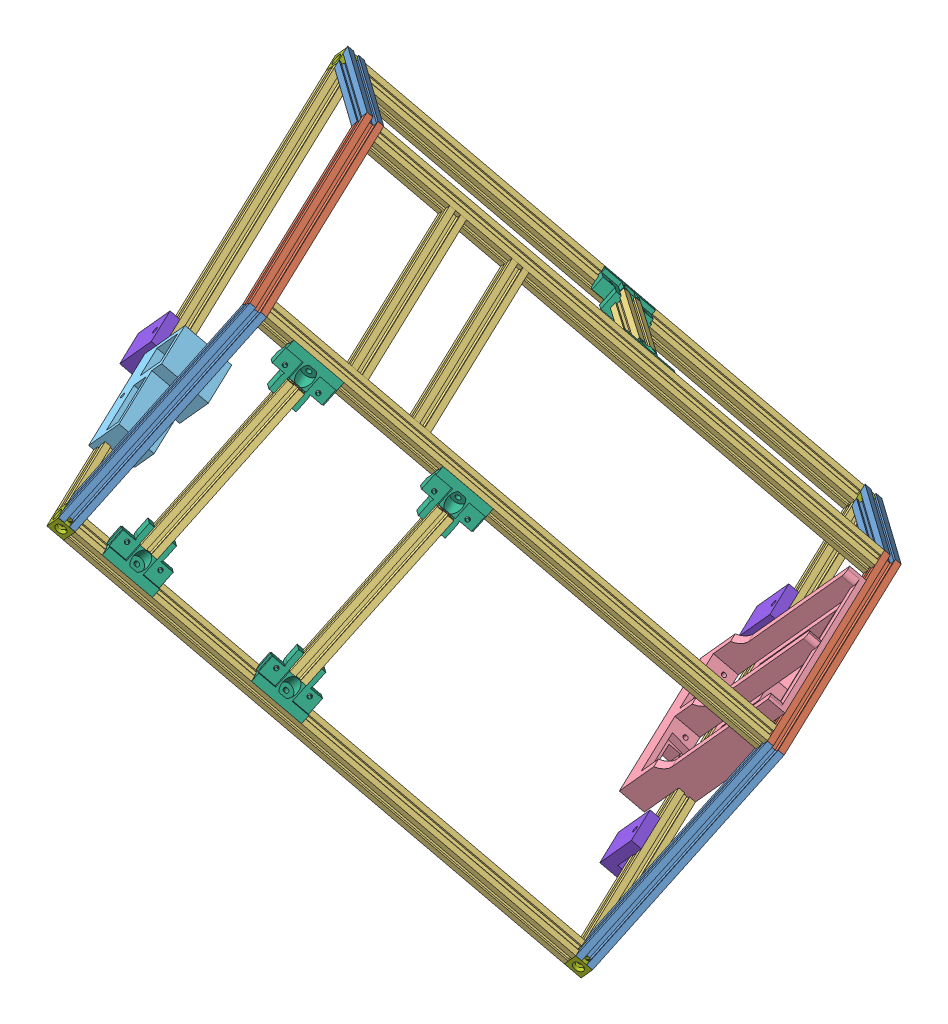
SolidWorks assembly ElectronicalBlock, configuration Default. Lengths in mm.
Overall size (353.4 324.72 408.45).
44 component instances, 11 part files, 96 mates.
Components (placement in the parent):
- MakerbeamVShapeElectronicalBlock-1: MakerbeamVShapeElectronicalBlock [Default] at (224.5108 -4.278 -44.3554) x (-0.701121 -0.374908 -0.606525) z (0.238672 0.678157 -0.695081) size (10 10 130)
- MakerbeamVShapeCentralElectronicalBlock-1: MakerbeamVShapeCentralElectronicalBlock [Default] at (214.846 108.8376 -246.4171) x (-0.664534 -0.74463 0.062619) z (0.327001 -0.21443 0.920375) size (10 10 125)
- MakerbeamVShapeElectronicalBlock-2: MakerbeamVShapeElectronicalBlock [Default] at (125.8295 60.432 -322.1031) x (-0.238672 -0.678157 0.695081) z (0.701121 0.374908 0.606525) size (10 10 130)
- Makerbeam50-1000mm-1: Makerbeam50-1000mm [288mm] at (127.2474 57.7735 -315.2814) x (0.664534 0.74463 -0.062619) z (0.327001 -0.21443 0.920375) size (10 10 288)
- Makerbeam50-1000mm-2: Makerbeam50-1000mm [300mm] at (-79.3205 251.6353 -202.1561) x (0.664534 0.74463 -0.062619) z (0.671911 -0.632097 -0.385991) size (10 10 300)
- Makerbeam50-1000mm-3: Makerbeam50-1000mm [300mm] at (11.5481 300.5551 -124.088) x (0.664534 0.74463 -0.062619) z (0.671911 -0.632097 -0.385991) size (10 10 300)
- Makerbeam50-1000mm-4: Makerbeam50-1000mm [300mm] at (49.0974 275.9323 -18.4022) x (0.664534 0.74463 -0.062619) z (0.671911 -0.632097 -0.385991) size (10 10 300)
- Makerbeam50-1000mm-5: Makerbeam50-1000mm [300mm] at (18.1259 187.7352 72.1157) x (0.664534 0.74463 -0.062619) z (0.671911 -0.632097 -0.385991) size (10 10 300)
- MakerbeamVShapeCentralElectronicalBlock-2: MakerbeamVShapeCentralElectronicalBlock [Default] at (6.4977 304.8243 -126.9172) x (-0.664534 -0.74463 0.062619) z (0.327001 -0.21443 0.920375) size (10 10 125)
- MakerbeamVShapeElectronicalBlock-3: MakerbeamVShapeElectronicalBlock [Default] at (16.1625 191.7087 75.1445) x (-0.701121 -0.374908 -0.606525) z (0.238672 0.678157 -0.695081) size (10 10 130)
- MakerbeamVShapeElectronicalBlock-4: MakerbeamVShapeElectronicalBlock [Default] at (-82.5188 256.4187 -202.6032) x (-0.238672 -0.678157 0.695081) z (0.701121 0.374908 0.606525) size (10 10 130)
- BatteriesBottomRack-1: BatteriesBottomRack [Default] at (181.2062 27.3347 -184.4602) x (-0.327001 0.21443 -0.920375) z (0.664534 0.74463 -0.062619) size (87 25 122.5)
- Makerbeam50-1000mm-6: Makerbeam50-1000mm [288mm] at (-81.045 253.7236 -195.6242) x (0.671911 -0.632097 -0.385991) z (0.327001 -0.21443 0.920375) size (10 10 288)
- PowerSwitchSupport-1: PowerSwitchSupport [Default] at (-6.8274 221.3425 7.3227) x (0.327001 -0.21443 0.920375) z (0.671911 -0.632097 -0.385991) size (60 35 28)
- WindowFixationMiddlesWithMakerBeam-1: WindowFixationMiddlesWithMakerBeam [Default] at (58.4475 311.7823 0.7661) x (-0.701343 -0.375537 -0.60588) z (-0.238021 -0.677809 0.695644) size (35.21 42 131.54)
  - Makerbeam50-1000mm-1: Makerbeam50-1000mm [100mm] at (29.5633 55.1843 28.8182) size (10 10 100)
  - WindowFixationMiddle-1: WindowFixationMiddle [Default] at (24.5633 55.0843 143.3182) x (-0.707107 0 -0.707107) z (0 -1 0) size (19.74 30.05 41)
  - WindowFixationMiddle-2: WindowFixationMiddle [Default] at (24.5633 55.0843 13.1973) x (-0.707107 0 0.707107) z (0 1 0) size (19.74 30.05 41)
- MakerBeam-cube-1: MakerBeam-cube [Default] at (221.4238 -3.9823 -50.2134) x (0.664534 0.74463 -0.062619) z (0.327001 -0.21443 0.920375) size (10 10 10)
- MakerBeam-cube-2: MakerBeam-cube [Default] at (127.2474 57.7735 -315.2814) x (0.664534 0.74463 -0.062619) z (-0.327001 0.21443 -0.920375) size (10 10 10)
- WindowFixationMiddlesWithMakerBeam-2: WindowFixationMiddlesWithMakerBeam [Default] at (-11.4548 201.6866 -272.8859) x (-0.23502 -0.676197 0.698229) z (0.702354 0.378432 0.602899) size (35.21 42 131.54)
  - Makerbeam50-1000mm-1: Makerbeam50-1000mm [100mm] at (29.5633 55.1843 28.8182) size (10 10 100)
  - WindowFixationMiddle-1: WindowFixationMiddle [Default] at (24.5633 55.0843 143.3182) x (-0.707107 0 -0.707107) z (0 -1 0) size (19.74 30.05 41)
  - WindowFixationMiddle-2: WindowFixationMiddle [Default] at (24.5633 55.0843 13.1973) x (-0.707107 0 0.707107) z (0 1 0) size (19.74 30.05 41)
- MakerBeam-cube-3: MakerBeam-cube [Default] at (-81.045 253.7236 -195.6242) x (-0.664534 -0.74463 0.062619) z (-0.327001 0.21443 -0.920375) size (10 10 10)
- ElectronicalToMechanicalTopFixation-1: ElectronicalToMechanicalTopFixation [Default] at (-32.013 212.2001 -29.3196) x (-0.327001 0.21443 -0.920375) z (-0.671911 0.632097 0.385991) size (20 27.5 16)
- Bracket_135Deg_25mm-1: Bracket_135Deg_25mm [Default] at (1.1699 303.3735 -120.8618) x (0.701121 0.374908 0.606525) z (0.671911 -0.632097 -0.385991) (suppressed, hidden)
- Bracket_135Deg_25mm-2: Bracket_135Deg_25mm [Default] at (39.3361 278.3461 -13.4396) x (0.327001 -0.21443 0.920375) z (0.671911 -0.632097 -0.385991) (suppressed, hidden)
- BracketPlainCorner45Deg_40mm-1: BracketPlainCorner45Deg_40mm [Default] at (-55.5212 273.0592 -169.9042) x (-0.701121 -0.374908 -0.606525) z (0.671911 -0.632097 -0.385991) (suppressed, hidden)
- Bracket_135Deg_25mm-3: Bracket_135Deg_25mm [Default] at (247.6844 82.3594 -132.9395) x (0.327001 -0.21443 0.920375) z (0.671911 -0.632097 -0.385991) (suppressed, hidden)
- Bracket_135Deg_25mm-4: Bracket_135Deg_25mm [Default] at (209.5182 107.3868 -240.3617) x (0.702572 0.37906 0.602251) z (0.671911 -0.632097 -0.385991) (suppressed, hidden)
- BracketPlainCorner45Deg_40mm-2: BracketPlainCorner45Deg_40mm [Default] at (0.239 207.2813 34.8779) x (0.327001 -0.21443 0.920375) z (0.671911 -0.632097 -0.385991) (suppressed, hidden)
- MakerBeam-cube-4: MakerBeam-cube [Default] at (13.1313 191.9678 69.4438) x (0.664534 0.74463 -0.062619) z (0.327001 -0.21443 0.920375) size (10 10 10)
- BracketPlainCorner45Deg_40mm-3: BracketPlainCorner45Deg_40mm [Default] at (146.452 50.1247 -282.2792) x (-0.327001 0.21443 -0.920375) z (-0.671911 0.632097 0.385991) (suppressed, hidden)
- BracketPlainCorner45Deg_40mm-4: BracketPlainCorner45Deg_40mm [Default] at (235.105 21.2041 -80.5966) x (-0.238672 -0.678157 0.695081) z (-0.671911 0.632097 0.385991) (suppressed, hidden)
- Pièce2^ElectronicalBlock-1: Pièce2^ElectronicalBlock [Default] at origin (virtual)
- ElectronicalToMechanicalTopFixation-2: ElectronicalToMechanicalTopFixation [Default] at (140.9633 39.4084 -248.3773) x (-0.327001 0.21443 -0.920375) z (-0.671911 0.632097 0.385991) size (20 27.5 16)
- ElectronicalToMechanicalTopFixation-3: ElectronicalToMechanicalTopFixation [Default] at (189.3595 7.6728 -112.1618) x (-0.327001 0.21443 -0.920375) z (-0.671911 0.632097 0.385991) size (20 27.5 16)
- Makerbeam50-1000mm-8: Makerbeam50-1000mm [105mm] at (46.9272 267.7383 -138.871) x (0.671911 -0.632097 -0.385991) z (0.327001 -0.21443 0.920375) size (10 10 105)
- Makerbeam50-1000mm-9: Makerbeam50-1000mm [105mm] at (71.9912 244.1436 -153.4588) x (0.664534 0.74463 -0.062619) z (0.327001 -0.21443 0.920375) size (10 10 105)
- WindowFixationMiddlesWithMakerBeam-3: WindowFixationMiddlesWithMakerBeam [Default] at (118.6058 255.3059 -33.6458) x (-0.701121 -0.374908 -0.606525) z (-0.238672 -0.678157 0.695081) size (35.21 42 131.54)
  - Makerbeam50-1000mm-1: Makerbeam50-1000mm [100mm] at (29.5633 55.1843 28.8182) size (10 10 100)
  - WindowFixationMiddle-1: WindowFixationMiddle [Default] at (24.5633 55.0843 143.3182) x (-0.707107 0 -0.707107) z (0 -1 0) size (19.74 30.05 41)
  - WindowFixationMiddle-2: WindowFixationMiddle [Default] at (24.5633 55.0843 13.1973) x (-0.707107 0 0.707107) z (0 1 0) size (19.74 30.05 41)
Mates (geometry in assembly coordinates):
- Coïncidente3: coincident aligned: plane of MakerbeamVShapeElectronicalBlock-1 through (255.6842 88.9175 -129.7534) normal (-0.671911 0.632097 0.385991); plane of MakerbeamVShapeCentralElectronicalBlock-1 through (253.3584 86.3113 -129.5342) normal (-0.671911 0.632097 0.385991)
- Coïncidente4: coincident anti-aligned: plane of MakerbeamVShapeElectronicalBlock-1 through (254.4035 76.0384 -136.7994) normal (-0.047803 0.483065 -0.874279); plane of MakerbeamVShapeCentralElectronicalBlock-1 through (247.6844 82.3594 -132.9395) normal (0.047803 -0.483065 0.874279)
- Coïncidente5: coincident anti-aligned: line of MakerbeamVShapeElectronicalBlock-1 through (255.6842 88.9175 -129.7534) axis (0.671911 -0.632097 -0.385991); line of MakerbeamVShapeCentralElectronicalBlock-1 through (258.0359 86.7052 -131.1043) axis (-0.671911 0.632097 0.385991)
- Coïncidente8: coincident aligned: line of MakerbeamVShapeCentralElectronicalBlock-1 through (217.1608 113.5089 -246.1512) axis (-0.671911 0.632097 0.385991); line of MakerbeamVShapeElectronicalBlock-2 through (217.1608 113.5089 -246.1512) axis (-0.671911 0.632097 0.385991)
- Coïncidente9: coincident aligned: plane of MakerbeamVShapeElectronicalBlock-1 through (251.127 86.4806 -133.6958) normal (-0.671911 0.632097 0.385991); plane of Makerbeam50-1000mm-1 through (219.061 0.2951 -48.3774) normal (-0.671911 0.632097 0.385991)
- Coïncidente10: coincident anti-aligned: plane of MakerbeamVShapeElectronicalBlock-1 through (226.7515 -2.5314 -56.2687) normal (-0.664534 -0.74463 0.062619); plane of Makerbeam50-1000mm-1 through (221.3869 2.9013 -48.5965) normal (0.664534 0.74463 -0.062619)
- Coïncidente11: coincident anti-aligned: plane of Makerbeam50-1000mm-1 through (214.7415 -4.545 -47.9703) normal (-0.671911 0.632097 0.385991); plane of Makerbeam50-1000mm-2 through (122.2529 62.0062 -317.9533) normal (0.671911 -0.632097 -0.385991)
- Coïncidente12: coincident aligned: plane of Makerbeam50-1000mm-1 through (221.3869 2.9013 -48.5965) normal (0.664534 0.74463 -0.062619); plane of Makerbeam50-1000mm-2 through (125.085 66.051 -319.6469) normal (0.664534 0.74463 -0.062619)
- Coïncidente13: coincident anti-aligned: plane of MakerbeamVShapeCentralElectronicalBlock-1 through (253.3584 86.3113 -129.5342) normal (-0.671911 0.632097 0.385991); plane of Makerbeam50-1000mm-3 through (213.1214 110.926 -239.8853) normal (0.671911 -0.632097 -0.385991)
- Coïncidente14: coincident aligned: plane of MakerbeamVShapeCentralElectronicalBlock-1 through (255.6842 88.9175 -129.7534) normal (0.664534 0.74463 -0.062619); plane of Makerbeam50-1000mm-3 through (218.0791 113.577 -235.5965) normal (0.664534 0.74463 -0.062619)
- Coïncidente15: coincident aligned: plane of MakerbeamVShapeCentralElectronicalBlock-1 through (253.3584 86.3113 -129.5342) normal (-0.671911 0.632097 0.385991); plane of MakerbeamVShapeElectronicalBlock-2 through (213.9737 113.3477 -242.3674) normal (-0.671911 0.632097 0.385991)
- Coïncidente16: coincident anti-aligned: plane of MakerbeamVShapeCentralElectronicalBlock-1 through (253.3584 86.3113 -129.5342) normal (-0.671911 0.632097 0.385991); plane of Makerbeam50-1000mm-4 through (250.6707 86.3032 -134.1994) normal (0.671911 -0.632097 -0.385991)
- Coïncidente17: coincident aligned: plane of MakerbeamVShapeCentralElectronicalBlock-1 through (255.6842 88.9175 -129.7534) normal (0.664534 0.74463 -0.062619); plane of Makerbeam50-1000mm-4 through (255.6284 88.9542 -129.9106) normal (0.664534 0.74463 -0.062619)
- Coïncidente18: coincident anti-aligned: plane of Makerbeam50-1000mm-1 through (214.7415 -4.545 -47.9703) normal (-0.671911 0.632097 0.385991); plane of Makerbeam50-1000mm-5 through (219.6992 -1.894 -43.6816) normal (0.671911 -0.632097 -0.385991)
- Coïncidente19: coincident aligned: plane of Makerbeam50-1000mm-1 through (221.3869 2.9013 -48.5965) normal (0.664534 0.74463 -0.062619); plane of Makerbeam50-1000mm-5 through (224.6569 0.757 -39.3928) normal (0.664534 0.74463 -0.062619)
- Coïncidente20: coincident anti-aligned: plane of Makerbeam50-1000mm-3 through (11.5481 300.5551 -124.088) normal (-0.671911 0.632097 0.385991); plane of MakerbeamVShapeCentralElectronicalBlock-2 through (54.055 278.5833 -14.1134) normal (0.671911 -0.632097 -0.385991)
- Coïncidente21: coincident aligned: plane of Makerbeam50-1000mm-3 through (218.0791 113.577 -235.5965) normal (0.664534 0.74463 -0.062619); plane of MakerbeamVShapeCentralElectronicalBlock-2 through (51.7034 280.7956 -12.7624) normal (0.664534 0.74463 -0.062619)
- Coïncidente22: coincident anti-aligned: plane of MakerbeamVShapeCentralElectronicalBlock-2 through (39.3361 278.3461 -13.4396) normal (0.047803 -0.483065 0.874279); plane of MakerbeamVShapeElectronicalBlock-3 through (46.0552 272.0252 -17.2995) normal (-0.047803 0.483065 -0.874279)
- Coïncidente23: coincident aligned: plane of MakerbeamVShapeCentralElectronicalBlock-2 through (45.0101 282.298 -10.0343) normal (-0.671911 0.632097 0.385991); plane of MakerbeamVShapeElectronicalBlock-3 through (47.3359 284.9042 -10.2535) normal (-0.671911 0.632097 0.385991)
- Coïncidente24: coincident anti-aligned: line of MakerbeamVShapeCentralElectronicalBlock-2 through (49.6876 282.6919 -11.6044) axis (-0.671911 0.632097 0.385991); line of MakerbeamVShapeElectronicalBlock-3 through (47.3359 284.9042 -10.2535) axis (0.671911 -0.632097 -0.385991)
- Coïncidente25: coincident anti-aligned: plane of MakerbeamVShapeCentralElectronicalBlock-1 through (209.5182 107.3868 -240.3617) normal (-0.556416 -0.08685 -0.826352); plane of MakerbeamVShapeElectronicalBlock-2 through (209.5182 107.3868 -240.3617) normal (0.556416 0.08685 0.826352)
- Coïncidente26: coincident aligned: plane of MakerbeamVShapeCentralElectronicalBlock-2 through (45.0101 282.298 -10.0343) normal (-0.671911 0.632097 0.385991); plane of MakerbeamVShapeElectronicalBlock-4 through (5.6254 309.3344 -122.8676) normal (-0.671911 0.632097 0.385991)
- Coïncidente27: coincident anti-aligned: plane of MakerbeamVShapeCentralElectronicalBlock-2 through (1.1699 303.3735 -120.8618) normal (-0.556416 -0.08685 -0.826352); plane of MakerbeamVShapeElectronicalBlock-4 through (1.1699 303.3735 -120.8618) normal (0.556416 0.08685 0.826352)
- Coïncidente28: coincident aligned: line of MakerbeamVShapeCentralElectronicalBlock-2 through (8.8125 309.4956 -126.6513) axis (-0.671911 0.632097 0.385991); line of MakerbeamVShapeElectronicalBlock-4 through (8.8125 309.4956 -126.6513) axis (-0.671911 0.632097 0.385991)
- Coïncidente29: coincident aligned: plane of Makerbeam50-1000mm-1 through (225.7801 -6.0258 -52.2373) normal (0.671911 -0.632097 -0.385991); plane of BatteriesBottomRack-1 through (228.4511 105.5407 -230.2887) normal (0.671911 -0.632097 -0.385991)
- Coïncidente31: coincident anti-aligned: plane of Makerbeam50-1000mm-1 through (221.3869 2.9013 -48.5965) normal (0.664534 0.74463 -0.062619); plane of BatteriesBottomRack-1 through (181.2062 27.3347 -184.4602) normal (-0.664534 -0.74463 0.062619)
- Coïncidente32: coincident anti-aligned: plane of MakerbeamVShapeElectronicalBlock-4 through (-80.0605 259.9375 -191.1326) normal (-0.664534 -0.74463 0.062619); plane of Makerbeam50-1000mm-6 through (17.4619 194.7428 68.5517) normal (0.664534 0.74463 -0.062619)
- Coïncidente34: coincident aligned: plane of MakerbeamVShapeElectronicalBlock-4 through (5.6254 309.3344 -122.8676) normal (-0.671911 0.632097 0.385991); plane of Makerbeam50-1000mm-6 through (10.7686 196.2452 71.2798) normal (-0.671911 0.632097 0.385991)
- Coïncidente36: coincident anti-aligned: plane of Makerbeam50-1000mm-6 through (13.0944 198.8514 71.0606) normal (0.664534 0.74463 -0.062619); plane of PowerSwitchSupport-1 through (-6.1675 207.6525 -28.6967) normal (-0.664534 -0.74463 0.062619)
- Parallèle1: parallel aligned: plane of Makerbeam50-1000mm-6 through (6.4491 191.4051 71.6868) normal (-0.671911 0.632097 0.385991); plane of PowerSwitchSupport-1 through (-6.8274 221.3425 7.3227) normal (-0.671911 0.632097 0.385991)
- Coïncidente38: coincident anti-aligned: plane of Makerbeam50-1000mm-6 through (10.7686 196.2452 71.2798) normal (-0.671911 0.632097 0.385991); plane of PowerSwitchSupport-1 through (-4.8116 219.4462 6.1647) normal (0.671911 -0.632097 -0.385991)
- Coïncidente39: coincident aligned: line of Makerbeam50-1000mm-4 through (255.6284 88.9542 -129.9106) axis (-0.671911 0.632097 0.385991); line of WindowFixationMiddlesWithMakerBeam-1/WindowFixationMiddle-2 through (85.1694 249.3125 -31.9876) axis (-0.671911 0.632097 0.385991)
- Coïncidente40: coincident anti-aligned: line of Makerbeam50-1000mm-5 through (224.6569 0.757 -39.3928) axis (-0.671911 0.632097 0.385991); line of WindowFixationMiddlesWithMakerBeam-1/WindowFixationMiddle-1 through (34.0406 180.0784 70.11) axis (0.671911 -0.632097 -0.385991)
- Coïncidente41: coincident anti-aligned: plane of Makerbeam50-1000mm-1 through (221.4238 -3.9823 -50.2134) normal (0.327001 -0.21443 0.920375); plane of MakerBeam-cube-1 through (221.4238 -3.9823 -50.2134) normal (-0.327001 0.21443 -0.920375)
- Coïncidente42: coincident aligned: plane of Makerbeam50-1000mm-1 through (217.0932 -6.7573 -49.3213) normal (-0.664534 -0.74463 0.062619); plane of MakerBeam-cube-1 through (224.7307 -13.0102 -42.6265) normal (-0.664534 -0.74463 0.062619)
- Coïncidente43: coincident aligned: plane of Makerbeam50-1000mm-5 through (222.331 -1.8492 -39.1736) normal (0.327001 -0.21443 0.920375); plane of MakerBeam-cube-1 through (224.6938 -6.1266 -41.0096) normal (0.327001 -0.21443 0.920375)
- Coïncidente44: coincident aligned: plane of Makerbeam50-1000mm-1 through (223.7865 -8.2597 -52.0494) normal (0.671911 -0.632097 -0.385991); plane of MakerBeam-cube-1 through (231.376 -5.5639 -43.2527) normal (0.671911 -0.632097 -0.385991)
- Coïncidente45: coincident anti-aligned: line of MakerbeamVShapeElectronicalBlock-1 through (224.6569 0.757 -39.3928) axis (0.671911 -0.632097 -0.385991); line of Makerbeam50-1000mm-5 through (224.6569 0.757 -39.3928) axis (-0.671911 0.632097 0.385991)
- Coïncidente46: coincident anti-aligned: plane of Makerbeam50-1000mm-1 through (127.2474 57.7735 -315.2814) normal (-0.327001 0.21443 -0.920375); plane of MakerBeam-cube-2 through (127.2474 57.7735 -315.2814) normal (0.327001 -0.21443 0.920375)
- Coïncidente47: coincident aligned: plane of Makerbeam50-1000mm-1 through (221.4606 -10.8659 -51.8302) normal (-0.664534 -0.74463 0.062619); plane of MakerBeam-cube-2 through (117.2952 59.3552 -322.2421) normal (-0.664534 -0.74463 0.062619)
- Coïncidente48: coincident aligned: plane of Makerbeam50-1000mm-1 through (214.7415 -4.545 -47.9703) normal (-0.671911 0.632097 0.385991); plane of MakerBeam-cube-2 through (123.9405 66.8015 -322.8683) normal (-0.671911 0.632097 0.385991)
- Coïncidente49: coincident anti-aligned: line of Makerbeam50-1000mm-3 through (214.8091 115.7213 -244.8002) axis (-0.671911 0.632097 0.385991); line of WindowFixationMiddlesWithMakerBeam-2/WindowFixationMiddle-1 through (110.3656 213.976 -184.8009) axis (0.671911 -0.632097 -0.385991)
- Coïncidente51: coincident anti-aligned: line of Makerbeam50-1000mm-2 through (123.9405 66.8015 -322.8683) axis (-0.671911 0.632097 0.385991); line of MakerBeam-cube-2 through (123.9405 66.8015 -322.8683) axis (0.671911 -0.632097 -0.385991)
- Coaxiale1: concentric aligned: cylinder of Makerbeam50-1000mm-2 through (122.2529 62.0062 -317.9533) axis (-0.671911 0.632097 0.385991) radius 1.25; cylinder of MakerBeam-cube-3 through (-80.6643 252.8995 -201.3841) axis (-0.671911 0.632097 0.385991) radius 3
- Coïncidente52: coincident aligned: plane of Makerbeam50-1000mm-2 through (119.6211 61.9614 -322.4612) normal (-0.327001 0.21443 -0.920375); plane of MakerBeam-cube-3 through (-84.315 255.8679 -204.828) normal (-0.327001 0.21443 -0.920375)
- Coïncidente53: coincident aligned: plane of Makerbeam50-1000mm-6 through (10.7686 196.2452 71.2798) normal (-0.671911 0.632097 0.385991); plane of MakerBeam-cube-3 through (-90.9972 255.3052 -202.5849) normal (-0.671911 0.632097 0.385991)
- Coïncidente54: coincident anti-aligned: plane of Makerbeam50-1000mm-6 through (-81.045 253.7236 -195.6242) normal (-0.327001 0.21443 -0.920375); plane of MakerBeam-cube-3 through (-81.045 253.7236 -195.6242) normal (0.327001 -0.21443 0.920375)
- Coïncidente56: coincident anti-aligned: plane of Makerbeam50-1000mm-6 through (10.7686 196.2452 71.2798) normal (-0.671911 0.632097 0.385991); plane of ElectronicalToMechanicalTopFixation-1 through (-32.013 212.2001 -29.3196) normal (0.671911 -0.632097 -0.385991)
- Coïncidente57: coincident anti-aligned: plane of Makerbeam50-1000mm-6 through (6.4491 191.4051 71.6868) normal (-0.671911 0.632097 0.385991); plane of ElectronicalToMechanicalTopFixation-1 through (-32.013 212.2001 -29.3196) normal (0.671911 -0.632097 -0.385991)
- Coïncidente58: coincident aligned: plane of Makerbeam50-1000mm-6 through (13.0944 198.8514 71.0606) normal (0.664534 0.74463 -0.062619); plane of ElectronicalToMechanicalTopFixation-1 through (-23.6371 224.087 -18.6609) normal (0.664534 0.74463 -0.062619)
- Coïncidente59: coincident aligned: plane of MakerbeamVShapeElectronicalBlock-4 through (4.9094 307.2999 -120.7823) normal (-0.671911 0.632097 0.385991); plane of Bracket_135Deg_25mm-1 through (-6.7664 290.8717 -114.2041) normal (-0.671911 0.632097 0.385991)
- Coïncidente60: coincident anti-aligned: plane of MakerbeamVShapeElectronicalBlock-4 through (6.4258 302.7141 -119.7005) normal (-0.238672 -0.678157 0.695081); plane of Bracket_135Deg_25mm-1 through (-9.639 287.6798 -139.8849) normal (0.238672 0.678157 -0.695081)
- Coïncidente61: coincident: point of MakerbeamVShapeCentralElectronicalBlock-2; point of Bracket_135Deg_25mm-1
- Coïncidente62: coincident anti-aligned: plane of MakerbeamVShapeCentralElectronicalBlock-2 through (43.0423 275.2456 -10.9783) normal (-0.664534 -0.74463 0.062619); plane of Bracket_135Deg_25mm-2 through (37.8802 277.3859 -40.3089) normal (0.664534 0.74463 -0.062619)
- Coïncidente63: coincident aligned: plane of MakerbeamVShapeCentralElectronicalBlock-2 through (43.0165 280.0641 -9.8465) normal (-0.671911 0.632097 0.385991); plane of Bracket_135Deg_25mm-2 through (27.3364 268.509 -18.2188) normal (-0.671911 0.632097 0.385991)
- Coïncidente64: coincident: line of MakerbeamVShapeElectronicalBlock-3 through (39.3361 278.3461 -13.4396) axis (0.739088 0.605889 0.29436); point of Bracket_135Deg_25mm-2
- Coïncidente65: coincident aligned: plane of MakerbeamVShapeElectronicalBlock-4 through (4.9094 307.2999 -120.7823) normal (-0.671911 0.632097 0.385991); plane of BracketPlainCorner45Deg_40mm-1 through (-72.7906 261.0722 -180.3357) normal (-0.671911 0.632097 0.385991)
- Coïncidente66: coincident anti-aligned: plane of MakerbeamVShapeElectronicalBlock-4 through (10.7932 298.6054 -122.2094) normal (-0.238672 -0.678157 0.695081); plane of BracketPlainCorner45Deg_40mm-1 through (-48.8021 266.7383 -173.7641) normal (0.238672 0.678157 -0.695081)
- Coïncidente67: coincident: point of MakerbeamVShapeElectronicalBlock-4; point of BracketPlainCorner45Deg_40mm-1
- Coïncidente68: coincident aligned: plane of MakerbeamVShapeElectronicalBlock-1 through (251.127 86.4806 -133.6958) normal (-0.671911 0.632097 0.385991); plane of Bracket_135Deg_25mm-3 through (235.6847 72.5223 -137.7187) normal (-0.671911 0.632097 0.385991)
- Coïncidente69: coincident anti-aligned: plane of MakerbeamVShapeElectronicalBlock-1 through (248.673 85.1684 -135.8186) normal (-0.701121 -0.374908 -0.606525); plane of Bracket_135Deg_25mm-3 through (254.4035 76.0384 -136.7994) normal (0.701121 0.374908 0.606525)
- Coïncidente70: coincident: line of MakerbeamVShapeCentralElectronicalBlock-1 through (247.6844 82.3594 -132.9395) axis (0.671911 -0.632097 -0.385991); point of Bracket_135Deg_25mm-3
- Coïncidente71: coincident aligned: plane of MakerbeamVShapeCentralElectronicalBlock-1 through (251.3648 84.0774 -129.3463) normal (-0.671911 0.632097 0.385991); plane of Bracket_135Deg_25mm-4 through (201.6375 94.8939 -233.6218) normal (-0.671911 0.632097 0.385991)
- Coïncidente74: coincident: line of MakerbeamVShapeCentralElectronicalBlock-1 through (209.5182 107.3868 -240.3617) axis (0.671911 -0.632097 -0.385991); point of Bracket_135Deg_25mm-4
- Coïncidente75: coincident aligned: plane of MakerbeamVShapeElectronicalBlock-3 through (42.7786 282.4673 -14.1959) normal (-0.671911 0.632097 0.385991); plane of BracketPlainCorner45Deg_40mm-2 through (11.0595 206.0878 55.668) normal (-0.671911 0.632097 0.385991)
- Coïncidente76: coincident anti-aligned: plane of MakerbeamVShapeElectronicalBlock-3 through (40.3247 281.1551 -16.3187) normal (-0.701121 -0.374908 -0.606525); plane of BracketPlainCorner45Deg_40mm-2 through (18.4032 193.4553 63.2311) normal (0.701121 0.374908 0.606525)
- Coïncidente77: coincident: line of Makerbeam50-1000mm-6 through (13.0944 198.8514 71.0606) axis (-0.327001 0.21443 -0.920375); point of BracketPlainCorner45Deg_40mm-2
- Coïncidente78: coincident aligned: plane of Makerbeam50-1000mm-6 through (8.8008 189.1928 70.3358) normal (-0.664534 -0.74463 0.062619); plane of MakerBeam-cube-4 through (16.4382 182.9399 77.0306) normal (-0.664534 -0.74463 0.062619)
- Coïncidente79: coincident aligned: plane of Makerbeam50-1000mm-5 through (214.7415 -4.545 -47.9703) normal (-0.664534 -0.74463 0.062619); plane of MakerBeam-cube-4 through (16.4382 182.9399 77.0306) normal (-0.664534 -0.74463 0.062619)
- Coïncidente82: coincident aligned: plane of Makerbeam50-1000mm-6 through (10.7686 196.2452 71.2798) normal (-0.671911 0.632097 0.385991); plane of MakerBeam-cube-4 through (16.3645 196.7071 80.2644) normal (-0.671911 0.632097 0.385991)
- Coïncidente83: coincident aligned: plane of Makerbeam50-1000mm-5 through (218.0115 -6.6893 -38.7666) normal (0.327001 -0.21443 0.920375); plane of MakerBeam-cube-4 through (16.4013 189.8235 78.6475) normal (0.327001 -0.21443 0.920375)
- Coïncidente84: coincident aligned: plane of MakerbeamVShapeElectronicalBlock-2 through (213.2577 111.3132 -240.2822) normal (-0.671911 0.632097 0.385991); plane of BracketPlainCorner45Deg_40mm-3 through (135.5577 65.0855 -299.8356) normal (-0.671911 0.632097 0.385991)
- Coïncidente85: coincident anti-aligned: plane of MakerbeamVShapeElectronicalBlock-2 through (214.7741 106.7273 -239.2004) normal (-0.238672 -0.678157 0.695081); plane of BracketPlainCorner45Deg_40mm-3 through (128.2878 63.9508 -310.6324) normal (0.238672 0.678157 -0.695081)
- Coïncidente86: coincident: point of MakerbeamVShapeElectronicalBlock-2; point of BracketPlainCorner45Deg_40mm-3
- Coïncidente87: coincident aligned: plane of MakerbeamVShapeElectronicalBlock-1 through (251.127 86.4806 -133.6958) normal (-0.671911 0.632097 0.385991); plane of BracketPlainCorner45Deg_40mm-4 through (219.4078 10.1011 -63.8318) normal (-0.671911 0.632097 0.385991)
- Coïncidente88: coincident anti-aligned: plane of MakerbeamVShapeElectronicalBlock-1 through (248.673 85.1684 -135.8186) normal (-0.701121 -0.374908 -0.606525); plane of BracketPlainCorner45Deg_40mm-4 through (228.3859 27.5251 -76.7367) normal (0.701121 0.374908 0.606525)
- Coïncidente89: coincident: line of Makerbeam50-1000mm-1 through (221.3869 2.9013 -48.5965) axis (-0.327001 0.21443 -0.920375); point of BracketPlainCorner45Deg_40mm-4
- Coïncidente90: coincident anti-aligned: plane of Makerbeam50-1000mm-1 through (219.061 0.2951 -48.3774) normal (-0.671911 0.632097 0.385991); plane of ElectronicalToMechanicalTopFixation-2 through (140.9633 39.4084 -248.3773) normal (0.671911 -0.632097 -0.385991)
- Coïncidente91: coincident aligned: plane of Makerbeam50-1000mm-1 through (221.3869 2.9013 -48.5965) normal (0.664534 0.74463 -0.062619); plane of ElectronicalToMechanicalTopFixation-2 through (149.3392 51.2954 -237.7186) normal (0.664534 0.74463 -0.062619)
- Coïncidente93: coincident aligned: plane of Makerbeam50-1000mm-1 through (221.3869 2.9013 -48.5965) normal (0.664534 0.74463 -0.062619); plane of ElectronicalToMechanicalTopFixation-3 through (197.7353 19.5597 -101.5031) normal (0.664534 0.74463 -0.062619)
- Coïncidente94: coincident anti-aligned: plane of Makerbeam50-1000mm-1 through (214.7415 -4.545 -47.9703) normal (-0.671911 0.632097 0.385991); plane of ElectronicalToMechanicalTopFixation-3 through (189.3595 7.6728 -112.1618) normal (0.671911 -0.632097 -0.385991)
- Coïncidente95: coincident anti-aligned: plane of Makerbeam50-1000mm-3 through (211.4338 106.1307 -234.9703) normal (0.327001 -0.21443 0.920375); plane of Makerbeam50-1000mm-8 through (46.9272 267.7383 -138.871) normal (-0.327001 0.21443 -0.920375)
- Coïncidente96: coincident aligned: plane of Makerbeam50-1000mm-3 through (218.0791 113.577 -235.5965) normal (0.664534 0.74463 -0.062619); plane of Makerbeam50-1000mm-8 through (85.5929 247.9982 -43.1237) normal (0.664534 0.74463 -0.062619)
- Parallèle2: parallel aligned: line of Makerbeam50-1000mm-4 through (255.6284 88.9542 -129.9106) axis (-0.671911 0.632097 0.385991); line of MakerbeamVShapeCentralElectronicalBlock-2 through (54.055 278.5833 -14.1134) axis (-0.671911 0.632097 0.385991)
- Parallèle3: parallel aligned: line of Makerbeam50-1000mm-4 through (252.3584 91.0985 -139.1144) axis (-0.671911 0.632097 0.385991); line of Makerbeam50-1000mm-8 through (83.5772 249.8945 -41.9658) axis (-0.671911 0.632097 0.385991)
- Coïncidente100: coincident aligned: line of MakerbeamVShapeCentralElectronicalBlock-1 through (217.1608 113.5089 -246.1512) axis (-0.671911 0.632097 0.385991); line of Makerbeam50-1000mm-3 through (214.8091 115.7213 -244.8002) axis (-0.671911 0.632097 0.385991)
- Coïncidente101: coincident aligned: line of Makerbeam50-1000mm-4 through (255.6284 88.9542 -129.9106) axis (-0.671911 0.632097 0.385991); line of MakerbeamVShapeCentralElectronicalBlock-2 through (54.055 278.5833 -14.1134) axis (-0.671911 0.632097 0.385991)
- Coïncidente102: coincident aligned: plane of Makerbeam50-1000mm-4 through (253.5029 90.3479 -135.893) normal (0.664534 0.74463 -0.062619); plane of Makerbeam50-1000mm-9 through (110.6569 224.4034 -57.7115) normal (0.664534 0.74463 -0.062619)
- Coïncidente103: coincident anti-aligned: plane of Makerbeam50-1000mm-4 through (250.0325 88.4922 -138.8952) normal (-0.327001 0.21443 -0.920375); plane of Makerbeam50-1000mm-9 through (106.3263 221.6284 -56.8194) normal (0.327001 -0.21443 0.920375)
- Distance1: distance = 10 mm anti-aligned: plane of Makerbeam50-1000mm-3 through (211.4338 106.1307 -234.9703) normal (0.327001 -0.21443 0.920375); plane of BatteriesBottomRack-1 through (215.0129 118.1826 -222.5689) normal (-0.327001 0.21443 -0.920375)
- Coïncidente105: coincident anti-aligned: line of Makerbeam50-1000mm-5 through (224.6569 0.757 -39.3928) axis (-0.671911 0.632097 0.385991); line of WindowFixationMiddlesWithMakerBeam-3/WindowFixationMiddle-1 through (94.111 123.5674 35.6015) axis (0.671911 -0.632097 -0.385991)
- Parallèle4: parallel anti-aligned: plane of Makerbeam50-1000mm-4 through (253.3025 86.3479 -129.6914) normal (0.327001 -0.21443 0.920375); plane of WindowFixationMiddlesWithMakerBeam-3/WindowFixationMiddle-2 through (145.3245 192.847 -66.4228) normal (-0.327001 0.21443 -0.920375)
- Distance2: distance = 50 mm aligned: plane of PowerSwitchSupport-1 through (-6.6309 199.9823 34.8718) normal (0.327001 -0.21443 0.920375); plane of MakerBeam-cube-4 through (16.4013 189.8235 78.6475) normal (0.327001 -0.21443 0.920375)
- Coïncidente108: coincident anti-aligned: plane of PowerSwitchSupport-1 through (-26.251 212.8481 -20.3507) normal (-0.327001 0.21443 -0.920375); plane of ElectronicalToMechanicalTopFixation-1 through (-41.9118 203.6097 -16.9389) normal (0.327001 -0.21443 0.920375)
- Distance3: distance = 80 mm aligned: plane of Makerbeam50-1000mm-2 through (120.5652 57.2109 -313.0383) normal (0.327001 -0.21443 0.920375); plane of ElectronicalToMechanicalTopFixation-2 through (131.0645 30.818 -235.9966) normal (0.327001 -0.21443 0.920375)
- Distance4: distance = 80 mm aligned: plane of ElectronicalToMechanicalTopFixation-3 through (191.1953 23.8483 -119.9106) normal (-0.327001 0.21443 -0.920375); plane of Makerbeam50-1000mm-5 through (217.0674 -1.9387 -48.1895) normal (-0.327001 0.21443 -0.920375)
